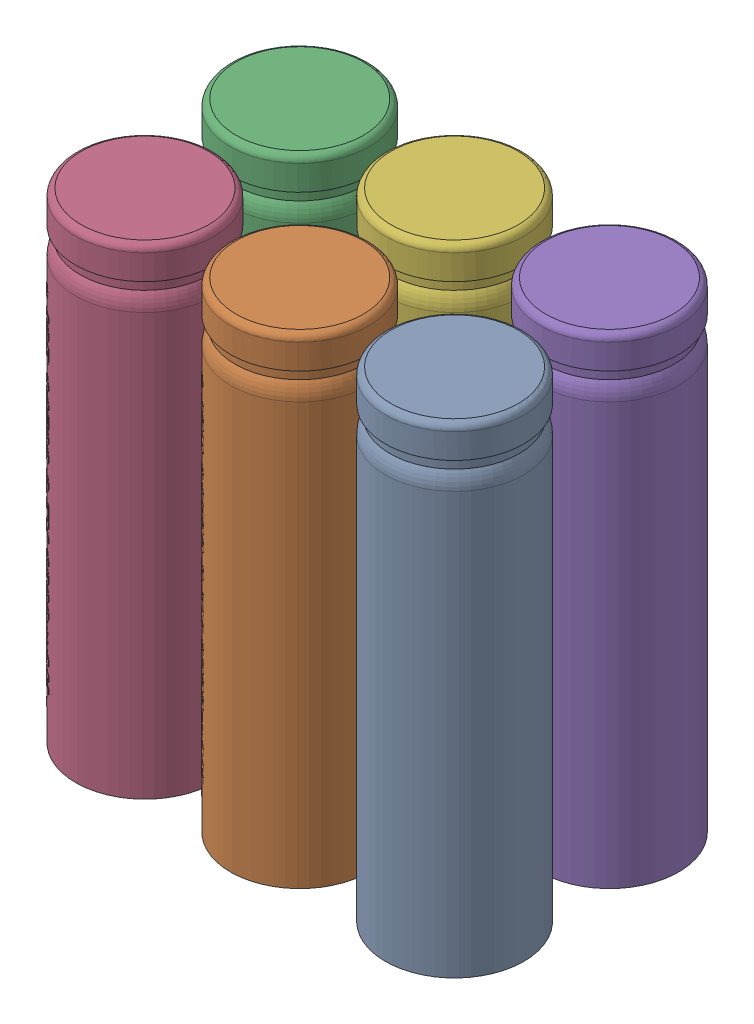
SolidWorks assembly 14500_batteries, configuration Default. Lengths in mm.
Overall size (51.26 48.92 35.49).
6 component instances, 1 part files, 13 mates.
Components (placement in the parent):
- ICR 14500-1: ICR 14500 [Default] at (0 -0.0254 0) x (-0.156747 0 0.987639) z (0 1 0) size (14.1 14.14 48.92)
- ICR 14500-2: ICR 14500 [Default] at (-15.7597 -0.0254 0) x (0.592213 0 0.805781) z (0 1 0) size (14.1 14.14 48.92)
- ICR 14500-3: ICR 14500 [Default] at (-31.5193 -0.0254 -15.7597) x (0.592213 0 0.805781) z (0 1 0) size (14.1 14.14 48.92)
- ICR 14500-4: ICR 14500 [Default] at (-31.5193 -0.0254 0) x (0.592213 0 0.805781) z (0 1 0) size (14.1 14.14 48.92)
- ICR 14500-5: ICR 14500 [Default] at (0 -0.0254 -15.7597) x (0.592213 0 0.805781) z (0 1 0) size (14.1 14.14 48.92)
- ICR 14500-6: ICR 14500 [Default] at (-15.7597 -0.0254 -15.7597) x (0.592213 0 0.805781) z (0 1 0) size (14.1 14.14 48.92)
Mates (geometry in assembly coordinates):
- Coincident3: coincident: point of ICR 14500-1; point of assembly
- Coincident4: coincident: point of ICR 14500-2; point of assembly
- Coincident5: coincident aligned: plane of ICR 14500-1 through (0 48.9204 0) normal (0 1 0); plane of ICR 14500-2 through (-15.7597 48.9204 0) normal (0 1 0)
- Coincident6: coincident: point of ICR 14500-5; point of assembly
- Coincident7: coincident: unknown of ICR 14500-6
- Coincident8: coincident: point of ICR 14500-3; point of assembly
- Coincident9: coincident: point of ICR 14500-4; point of assembly
- Coincident10: coincident aligned: plane of ICR 14500-2 through (-15.7597 48.9204 0) normal (0 1 0); plane of ICR 14500-4 through (-31.5193 48.9204 0) normal (0 1 0)
- Coincident11: coincident aligned: plane of ICR 14500-4 through (-31.5193 48.9204 0) normal (0 1 0); plane of ICR 14500-5 through (0 48.9204 -15.7597) normal (0 1 0)
- Coincident12: coincident aligned: plane of ICR 14500-4 through (-31.5193 48.9204 0) normal (0 1 0); plane of ICR 14500-6 through (-15.7597 48.9204 -15.7597) normal (0 1 0)
- Coincident13: coincident aligned: plane of ICR 14500-3 through (-31.5193 48.9204 -15.7597) normal (0 1 0); plane of ICR 14500-4 through (-31.5193 48.9204 0) normal (0 1 0)
- Coincident14: coincident aligned: plane of ICR 14500-1 through (0 48.9204 0) normal (0 1 0); plane of ICR 14500-4 through (-31.5193 48.9204 0) normal (0 1 0)
- Parallel1: parallel aligned: plane of ICR 14500-3 through (-31.5193 48.9204 -15.7597) normal (0 1 0)
